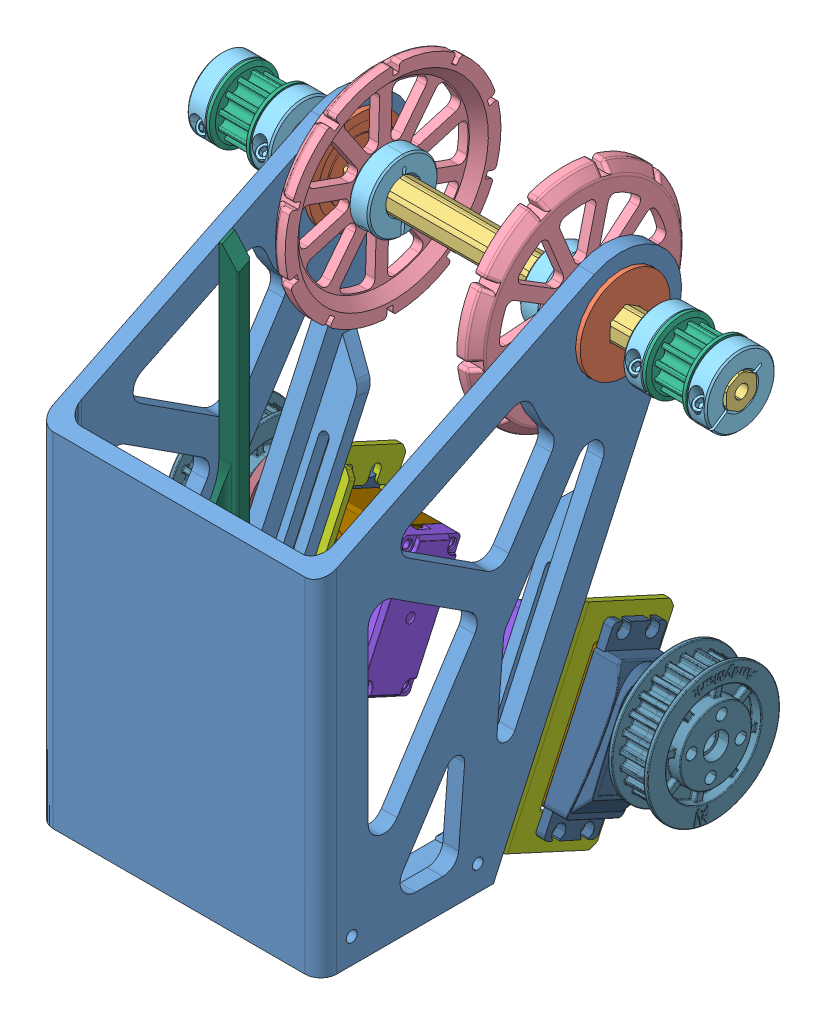
SolidWorks assembly Intake, configuration Default. Lengths in mm.
Overall size (165 189.33 142.34).
35 component instances, 15 part files, 67 mates.
Components (placement in the parent):
- IntakeBody-1: IntakeBody [Default] at (-26.4848 14.4337 189.9954) size (90 153.43 114.54)
- 0_375_Hex_ID_x_1_125_OD_x_0_313_WD_Flanged_Bearing_217-2735.step-1: 0_375_Hex_ID_x_1_125_OD_x_0_313_WD_Flanged_Bearing_217-2735.step [Default] at (-32.8348 143.5737 98.7454) x (0 -0.525688 -0.850678) z (0 -0.850678 0.525688) size (31.12 7.94 31.12)
- 0_375_Hex_ID_x_1_125_OD_x_0_313_WD_Flanged_Bearing_217-2735.step-2: 0_375_Hex_ID_x_1_125_OD_x_0_313_WD_Flanged_Bearing_217-2735.step [Default] at (59.8652 143.5737 98.7454) x (0 0.525688 0.850678) z (0 -0.850678 0.525688) size (31.12 7.94 31.12)
- IntakeHex-1: IntakeHex [Default] at (-360.4391 143.5692 98.7381) x (0 0.999552 -0.02992) z (-1 0 0) size (10.24 9.53 165)
- IntakeWheel-1: IntakeWheel [Default] at (-19.9773 143.4781 98.5907) x (0 0.02992 0.999552) z (1 0 0) size (68.5 68.38 6)
- IntakeWheel-2: IntakeWheel [Default] at (46.6554 143.396 98.7433) x (0 -0.850678 0.525688) z (-1 0 0) size (68.5 68.38 6)
- Clamping_Shaft_Collar_-_3_8_Hex_ID_217-2739.step-1: Clamping_Shaft_Collar_-_3_8_Hex_ID_217-2739.step [Default] at (40.4804 143.7158 98.7337) x (0 -0.999552 0.02992) z (1 0 0) size (22.21 22.23 6.35)
- Clamping_Shaft_Collar_-_3_8_Hex_ID_217-2739.step-2: Clamping_Shaft_Collar_-_3_8_Hex_ID_217-2739.step [Default] at (-13.8023 143.6387 98.6089) x (0 -0.999552 0.02992) z (1 0 0) size (22.21 22.23 6.35)
- intakePulley-1: intakePulley [Default] at (-61.8891 143.6602 98.8854) x (0 -0.850678 0.525688) z (-1 0 0) size (22.2 22.2 13.72)
- intakePulley-2: intakePulley [Default] at (76.4671 143.7423 98.7329) x (0 -0.850678 0.525688) z (-1 0 0) size (22.2 22.2 13.72)
- REV-41-1485 (2).step-1: REV-41-1485 (2).step [Default] at (57.0152 36.4401 108.0667) x (0 -0.908556 0.417762) z (1 0 0) size (62 34 15)
- REV-41-1485 (2).step-2: REV-41-1485 (2).step [Default] at (-29.9848 36.4401 108.0667) x (0 0.908556 -0.417762) z (-1 0 0) size (62 34 15)
- REV-41-1097 (1).STEP-1: REV-41-1097 (1).STEP [Default] at (30.4566 34.9779 104.8867) x (0 -0.417762 -0.908556) z (-1 0 0) size (24.05 54 43.73)
  - A.STEP-1: A.STEP [Default] at origin size (20.15 40.13 8.54)
  - E.STEP-1: E.STEP [Default] at origin size (20.15 40.15 20.1)
  - C.STEP-1: C.STEP [Default] at origin size (24.05 54 13.28)
  - B.STEP-1: B.STEP [Default] at origin size (9 9 4.4)
  - D.STEP-1: D.STEP [Default] at (0 -10.0526 -30.1) x (-1 0 0) z (0 0 1) size (17.21 17.2 14.7)
- REV-41-1097 (1).STEP-2: REV-41-1097 (1).STEP [Default] at (-2.1626 34.9779 104.8867) x (0 0.417762 0.908556) z (1 0 0) size (24.05 54 43.73)
  - A.STEP-1: A.STEP [Default] at origin size (20.15 40.13 8.54)
  - E.STEP-1: E.STEP [Default] at origin size (20.15 40.15 20.1)
  - C.STEP-1: C.STEP [Default] at origin size (24.05 54 13.28)
  - B.STEP-1: B.STEP [Default] at origin size (9 9 4.4)
  - D.STEP-1: D.STEP [Default] at (0 -10.0526 -30.1) x (-1 0 0) z (0 0 1) size (17.21 17.2 14.7)
- IntakeServoHorn-1: IntakeServoHorn [Default] at (-43.8626 44.1112 100.6871) x (0 0.984266 -0.176693) z (0 0.176693 0.984266) size (25 6 25)
- am-3401+24+tooth+HTD+pulley+half+6mm+bore-1: am-3401+24+tooth+HTD+pulley+half+6mm+bore [Default] at (-55.3651 25.5759 79.8226) x (-1 0 0) z (0 -0.994181 -0.107721) size (8.91 42 42)
- am-3401+24+tooth+HTD+pulley+half+6mm+bore-2: am-3401+24+tooth+HTD+pulley+half+6mm+bore [Default] at (-55.3651 62.8072 126.1025) x (1 0 0) z (0 -0.107721 0.994181) size (8.91 42 42)
- am-3401+24+tooth+HTD+pulley+half+6mm+bore-3: am-3401+24+tooth+HTD+pulley+half+6mm+bore [Default] at (83.6591 28.2252 125.7796) x (-1 0 0) z (0 0.2192 0.97568) size (8.91 42 42)
- am-3401+24+tooth+HTD+pulley+half+6mm+bore-4: am-3401+24+tooth+HTD+pulley+half+6mm+bore [Default] at (83.6591 59.9973 75.5947) x (1 0 0) z (0 0.97568 -0.2192) size (8.91 42 42)
- IntakeServoHorn-2: IntakeServoHorn [Default] at (72.1566 44.1112 100.6871) x (0 -0.97568 0.2192) z (0 0.2192 0.97568) size (25 6 25)
- Clamping_Shaft_Collar_-_3_8_Hex_ID_217-2739.step-7: Clamping_Shaft_Collar_-_3_8_Hex_ID_217-2739.step [Default] at (-65.0641 143.5692 98.7381) x (0 -0.822941 0.568127) z (1 0 0) size (22.21 22.23 6.35)
- Clamping_Shaft_Collar_-_3_8_Hex_ID_217-2739.step-8: Clamping_Shaft_Collar_-_3_8_Hex_ID_217-2739.step [Default] at (-44.9981 143.6602 98.8854) x (0 -0.559091 0.829106) z (1 0 0) size (22.21 22.23 6.35)
- Clamping_Shaft_Collar_-_3_8_Hex_ID_217-2739.step-9: Clamping_Shaft_Collar_-_3_8_Hex_ID_217-2739.step [Default] at (73.2921 143.5692 98.7381) x (0 -0.559091 0.829106) z (1 0 0) size (22.21 22.23 6.35)
- Clamping_Shaft_Collar_-_3_8_Hex_ID_217-2739.step-10: Clamping_Shaft_Collar_-_3_8_Hex_ID_217-2739.step [Default] at (93.3581 143.5692 98.7381) x (0 -0.559091 0.829106) z (1 0 0) size (22.21 22.23 6.35)
- Part2-1: Part2 [Default] at (-26.4848 14.4337 189.9954) x (0 0 -1) z (1 0 0) size (49.9 131.79 6)
Mates (geometry in assembly coordinates):
- Concentric1: concentric: cylinder of IntakeBody-1 through (-26.4848 143.5737 98.7454) axis (-1 0 0) radius 14.4375; cylinder of 0_375_Hex_ID_x_1_125_OD_x_0_313_WD_Flanged_Bearing_217-2735.step-1 through (-32.8348 143.5737 98.7454) axis (1 0 0) radius 14.2748
- Coincident1: coincident: plane of IntakeBody-1 through (-26.4848 14.4337 139.1954) normal (1 0 0); plane of 0_375_Hex_ID_x_1_125_OD_x_0_313_WD_Flanged_Bearing_217-2735.step-1 through (-26.4848 135.3953 85.511) normal (-1 0 0)
- Concentric2: concentric: cylinder of IntakeBody-1 through (53.5152 143.5737 98.7454) axis (1 0 0) radius 14.4375; cylinder of 0_375_Hex_ID_x_1_125_OD_x_0_313_WD_Flanged_Bearing_217-2735.step-2 through (59.8652 143.5737 98.7454) axis (-1 0 0) radius 14.2748
- Coincident2: coincident: plane of IntakeBody-1 through (53.5152 14.4337 139.1954) normal (-1 0 0); plane of 0_375_Hex_ID_x_1_125_OD_x_0_313_WD_Flanged_Bearing_217-2735.step-2 through (53.5152 151.7521 111.9799) normal (1 0 0)
- Coincident3: coincident: plane of 0_375_Hex_ID_x_1_125_OD_x_0_313_WD_Flanged_Bearing_217-2735.step-1 through (-6.9368 140.6783 94.06) normal (0 0.880598 0.473865); plane of IntakeHex-1 through (-817.6391 140.6783 94.06) normal (0 -0.880598 -0.473865)
- Coincident4: coincident: plane of 0_375_Hex_ID_x_1_125_OD_x_0_313_WD_Flanged_Bearing_217-2735.step-1 through (-6.9368 146.1837 93.8952) normal (0 0.02992 0.999552); plane of IntakeHex-1 through (-817.6391 146.1751 93.8954) normal (0 -0.02992 -0.999552)
- Parallel2: parallel: plane of 0_375_Hex_ID_x_1_125_OD_x_0_313_WD_Flanged_Bearing_217-2735.step-2 through (33.9671 149.0792 98.5806) normal (0 -0.880598 -0.473865); plane of IntakeHex-1 through (-817.6391 146.4601 103.4162) normal (0 0.880598 0.473865)
- Coincident6: coincident: plane of IntakeHex-1 through (-817.6391 140.9633 103.5807) normal (0 0.02992 0.999552); plane of IntakeWheel-1 through (-16.9773 140.7901 103.5859) normal (0 -0.02992 -0.999552)
- Coincident7: coincident: plane of IntakeHex-1 through (-817.6391 146.4601 103.4162) normal (0 0.880598 0.473865); plane of IntakeWheel-1 through (-16.9773 146.4601 103.4162) normal (0 -0.880598 -0.473865)
- Coincident8: coincident: plane of IntakeHex-1 through (-817.6391 146.4601 103.4162) normal (0 0.880598 0.473865); plane of IntakeWheel-2 through (43.6554 149.066 98.5735) normal (0 -0.880598 -0.473865)
- Coincident9: coincident: plane of IntakeHex-1 through (-817.6391 149.066 98.5735) normal (0 0.850678 -0.525688); plane of IntakeWheel-2 through (43.6554 146.084 93.7481) normal (0 -0.850678 0.525688)
- Coincident10: coincident: plane of IntakeHex-1 through (-817.6391 138.0724 98.9026) normal (0 -0.850678 0.525688); plane of Clamping_Shaft_Collar_-_3_8_Hex_ID_217-2739.step-1 through (43.6554 138.0724 98.9026) normal (0 0.850678 -0.525688)
- Coincident11: coincident: plane of IntakeHex-1 through (-817.6391 140.6783 94.06) normal (0 -0.880598 -0.473865); plane of Clamping_Shaft_Collar_-_3_8_Hex_ID_217-2739.step-1 through (43.6554 140.7478 93.9308) normal (0 0.880598 0.473865)
- Coincident12: coincident: plane of IntakeWheel-2 through (43.6554 143.396 98.7433) normal (-1 0 0); plane of Clamping_Shaft_Collar_-_3_8_Hex_ID_217-2739.step-1 through (43.6554 143.7158 98.7337) normal (1 0 0)
- Coincident13: coincident: plane of IntakeHex-1 through (-817.6391 140.9633 103.5807) normal (0 0.02992 0.999552); plane of Clamping_Shaft_Collar_-_3_8_Hex_ID_217-2739.step-2 through (-10.6273 140.9633 103.5807) normal (0 -0.02992 -0.999552)
- Coincident14: coincident: plane of IntakeHex-1 through (-817.6391 138.0724 98.9026) normal (0 -0.850678 0.525688); plane of Clamping_Shaft_Collar_-_3_8_Hex_ID_217-2739.step-2 through (-10.6273 137.9953 98.7779) normal (0 0.850678 -0.525688)
- Coincident15: coincident: plane of IntakeWheel-1 through (-16.9773 143.4781 98.5907) normal (1 0 0); plane of Clamping_Shaft_Collar_-_3_8_Hex_ID_217-2739.step-2 through (-16.9773 143.6387 98.6089) normal (-1 0 0)
- Coincident16: coincident: plane of IntakeHex-1 through (-817.6391 140.6783 94.06) normal (0 -0.880598 -0.473865); plane of intakePulley-1 through (-48.1731 140.6783 94.06) normal (0 0.880598 0.473865)
- Coincident17: coincident: plane of IntakeHex-1 through (-817.6391 146.1751 93.8954) normal (0 -0.02992 -0.999552); plane of intakePulley-1 through (-48.1731 146.3482 93.8903) normal (0 0.02992 0.999552)
- Coincident18: coincident: plane of IntakeHex-1 through (-817.6391 140.6783 94.06) normal (0 -0.880598 -0.473865); plane of intakePulley-2 through (90.1831 140.7604 93.9074) normal (0 0.880598 0.473865)
- Coincident19: coincident: plane of IntakeHex-1 through (-817.6391 138.0724 98.9026) normal (0 -0.850678 0.525688); plane of intakePulley-2 through (90.1831 138.0724 98.9026) normal (0 0.850678 -0.525688)
- Coincident22: coincident: plane of IntakeBody-1 through (53.5152 -5.7206 146.1635) normal (0 -0.417762 -0.908556); plane of REV-41-1485 (2).step-1 through (57.0152 43.542 123.5121) normal (0 0.417762 0.908556)
- Parallel3: parallel: plane of IntakeBody-1 through (58.5152 14.4337 193.9954) normal (1 0 0); plane of REV-41-1485 (2).step-1 through (57.0152 36.4401 108.0667) normal (1 0 0)
- Parallel4: parallel: plane of IntakeBody-1 through (-31.4848 14.4337 193.9954) normal (-1 0 0); plane of REV-41-1485 (2).step-2 through (-29.9848 36.4401 108.0667) normal (-1 0 0)
- Coincident25: coincident: plane of IntakeBody-1 through (53.5152 -5.7206 146.1635) normal (0 -0.417762 -0.908556); plane of REV-41-1485 (2).step-2 through (-29.9848 43.542 123.5121) normal (0 0.417762 0.908556)
- Concentric6: concentric: cylinder of REV-41-1485 (2).step-1 through (57.0152 59.5535 99.0899) axis (1 0 0) radius 1.7; cylinder of REV-41-1097 (1).STEP-1/C.STEP-1 through (59.8066 59.5535 99.0899) axis (1 0 0) radius 2.25
- Concentric7: concentric: cylinder of REV-41-1485 (2).step-2 through (-29.9848 59.5535 99.0899) axis (-1 0 0) radius 1.7; cylinder of ? through (-31.5126 59.5535 99.0899) axis (-1 0 0) radius 2.25
- Concentric8: concentric: cylinder of REV-41-1485 (2).step-2 through (-29.9848 55.3759 90.0043) axis (-1 0 0) radius 1.7; cylinder of ? through (-31.5126 55.3759 90.0043) axis (-1 0 0) radius 2.25
- Concentric9: concentric: circle of REV-41-1097 (1).STEP-2/D.STEP-1; circle of IntakeServoHorn-1
- Coincident31: coincident: circle of REV-41-1097 (1).STEP-2/D.STEP-1; plane of IntakeServoHorn-1 through (-45.8626 44.1112 100.6871) normal (1 0 0)
- Coincident32: coincident: plane of IntakeServoHorn-1 through (-48.3626 44.1112 100.6871) normal (-1 0 0); plane of am-3401+24+tooth+HTD+pulley+half+6mm+bore-1 through (-48.3626 44.1916 102.9626) normal (1 0 0)
- Concentric14: concentric: cylinder of IntakeServoHorn-1 through (-38.3626 36.2371 102.1007) axis (-1 0 0) radius 1.6; cylinder of am-3401+24+tooth+HTD+pulley+half+6mm+bore-1 through (-57.2701 36.2371 102.1007) axis (1 0 0) radius 1.778
- Concentric15: concentric: cylinder of am-3401+24+tooth+HTD+pulley+half+6mm+bore-1 through (-57.2701 36.2371 102.1007) axis (1 0 0) radius 1.778; cylinder of am-3401+24+tooth+HTD+pulley+half+6mm+bore-2 through (-53.4601 36.2371 102.1007) axis (-1 0 0) radius 1.778
- Concentric16: concentric: cylinder of am-3401+24+tooth+HTD+pulley+half+6mm+bore-1 through (-57.2701 44.1916 102.9626) axis (1 0 0) radius 3.1; cylinder of am-3401+24+tooth+HTD+pulley+half+6mm+bore-2 through (-53.4601 44.1916 102.9626) axis (-1 0 0) radius 3.1
- Coincident33: coincident: plane of am-3401+24+tooth+HTD+pulley+half+6mm+bore-1 through (-55.3651 45.9927 85.1904) normal (-1 0 0); plane of am-3401+24+tooth+HTD+pulley+half+6mm+bore-2 through (-55.3651 61.937 105.0098) normal (1 0 0)
- Concentric17: concentric: cylinder of am-3401+24+tooth+HTD+pulley+half+6mm+bore-4 through (85.5641 51.9177 98.9333) axis (-1 0 0) radius 1.778; cylinder of IntakeServoHorn-2 through (66.6566 51.9167 98.9335) axis (1 0 0) radius 1.6
- Concentric18: concentric: cylinder of am-3401+24+tooth+HTD+pulley+half+6mm+bore-3 through (81.7541 51.9177 98.9333) axis (1 0 0) radius 1.778; cylinder of am-3401+24+tooth+HTD+pulley+half+6mm+bore-4 through (85.5641 51.9177 98.9333) axis (-1 0 0) radius 1.778
- Coincident34: coincident: plane of am-3401+24+tooth+HTD+pulley+half+6mm+bore-3 through (83.6591 26.7101 104.7234) normal (-1 0 0); plane of am-3401+24+tooth+HTD+pulley+half+6mm+bore-4 through (83.6591 40.3165 83.2317) normal (1 0 0)
- Concentric20: concentric: cylinder of am-3401+24+tooth+HTD+pulley+half+6mm+bore-3 through (81.7541 44.1112 100.6871) axis (1 0 0) radius 3.1; cylinder of am-3401+24+tooth+HTD+pulley+half+6mm+bore-4 through (85.5641 44.1112 100.6871) axis (-1 0 0) radius 3.1
- Coincident35: coincident: plane of am-3401+24+tooth+HTD+pulley+half+6mm+bore-4 through (76.6566 44.1112 100.6871) normal (-1 0 0); plane of IntakeServoHorn-2 through (76.6566 44.1112 100.6871) normal (1 0 0)
- Concentric21: concentric: circle of REV-41-1097 (1).STEP-1/D.STEP-1; cylinder of IntakeServoHorn-2 through (76.6566 44.1112 100.6871) axis (-1 0 0) radius 1.75
- Coincident37: coincident: plane of REV-41-1097 (1).STEP-1/D.STEP-1 through (74.1566 44.1112 100.6871) normal (1 0 0); plane of IntakeServoHorn-2 through (74.1566 44.1112 100.6871) normal (-1 0 0)
- Coincident38: coincident: plane of intakePulley-1 through (-60.3651 143.6602 98.8854) normal (1 0 0); plane of am-3401+24+tooth+HTD+pulley+half+6mm+bore-2 through (-60.3651 44.1916 102.9626) normal (1 0 0)
- Coincident40: coincident: plane of intakePulley-2 through (88.6591 143.7423 98.7329) normal (-1 0 0); plane of am-3401+24+tooth+HTD+pulley+half+6mm+bore-3 through (88.6591 44.1112 100.6871) normal (-1 0 0)
- BeltMate1: belt = 41.492 : 19.431 mm: circle of intakePulley-2; circle of am-3401+24+tooth+HTD+pulley+half+6mm+bore-4
- BeltMate2: belt = 19.431 : 41.492 mm: circle of am-3401+24+tooth+HTD+pulley+half+6mm+bore-2; circle of intakePulley-1
- Concentric23: concentric: cylinder of REV-41-1485 (2).step-1 through (57.0152 55.3759 90.0043) axis (1 0 0) radius 1.7; cylinder of REV-41-1097 (1).STEP-1/C.STEP-1 through (59.8066 55.3759 90.0043) axis (1 0 0) radius 2.25
- Concentric25: concentric: circle of IntakeBody-1; cylinder of REV-41-1485 (2).step-1 through (49.5152 21.7367 133.5384) axis (0 0.417762 0.908556) radius 1.7
- Concentric26: concentric: circle of IntakeBody-1; circle of REV-41-1485 (2).step-2
- Concentric27: concentric: cylinder of am-3401+24+tooth+HTD+pulley+half+6mm+bore-3 through (81.7541 44.1112 100.6871) axis (1 0 0) radius 3.1; cylinder of IntakeServoHorn-2 through (74.1566 44.1112 100.6871) axis (1 0 0) radius 12.5
- Concentric28: concentric: cylinder of IntakeHex-1 through (96.7609 143.5692 98.7381) axis (-1 0 0) radius 2.1; cylinder of Clamping_Shaft_Collar_-_3_8_Hex_ID_217-2739.step-7 through (-61.8891 143.5692 98.7381) axis (-1 0 0) radius 11.1125
- Coincident41: coincident: circle of intakePulley-1; plane of Clamping_Shaft_Collar_-_3_8_Hex_ID_217-2739.step-7 through (-61.8891 143.5692 98.7381) normal (1 0 0)
- Concentric29: concentric: cylinder of intakePulley-1 through (-62.5749 143.6602 98.8854) axis (1 0 0) radius 11.0998; cylinder of Clamping_Shaft_Collar_-_3_8_Hex_ID_217-2739.step-8 through (-41.8231 143.6602 98.8854) axis (-1 0 0) radius 11.1125
- Coincident42: coincident: circle of intakePulley-1; plane of Clamping_Shaft_Collar_-_3_8_Hex_ID_217-2739.step-8 through (-48.1731 143.6602 98.8854) normal (-1 0 0)
- Concentric30: concentric: cylinder of IntakeHex-1 through (96.7609 143.5692 98.7381) axis (-1 0 0) radius 2.1; cylinder of Clamping_Shaft_Collar_-_3_8_Hex_ID_217-2739.step-10 through (96.5331 143.5692 98.7381) axis (-1 0 0) radius 11.1125
- Coincident43: coincident: circle of intakePulley-2; plane of Clamping_Shaft_Collar_-_3_8_Hex_ID_217-2739.step-10 through (90.1831 143.5692 98.7381) normal (-1 0 0)
- Concentric31: concentric: cylinder of IntakeHex-1 through (96.7609 143.5692 98.7381) axis (-1 0 0) radius 2.1; cylinder of Clamping_Shaft_Collar_-_3_8_Hex_ID_217-2739.step-9 through (76.4671 143.5692 98.7381) axis (-1 0 0) radius 11.1125
- Coincident44: coincident: circle of intakePulley-2; plane of Clamping_Shaft_Collar_-_3_8_Hex_ID_217-2739.step-9 through (76.4671 143.5692 98.7381) normal (1 0 0)
- Coincident46: coincident: plane of IntakeHex-1 through (-68.2391 143.5692 98.7381) normal (-1 0 0); plane of Clamping_Shaft_Collar_-_3_8_Hex_ID_217-2739.step-7 through (-68.2391 143.5692 98.7381) normal (-1 0 0)
- InPlace1: in place: plane of IntakeBody-1 through (-26.4848 14.4337 139.1954) normal (0 1 0); plane of ? through (0 14.4337 0) normal (0 1 0); moOrthogonalPlaneRef_w of IntakeBody-1 through (-26.4848 14.4337 139.1954) normal (0 1 0); plane of ? through (0 14.4337 0) normal (0 0 -1); plane of IntakeBody-1 through (-26.4848 14.4337 139.1954) normal (0 1 0); plane of ? through (0 14.4337 0) normal (1 0 0); plane of IntakeBody-1 through (-26.4848 14.4337 139.1954) normal (0 1 0); unknown of ?
- Coincident47: coincident: plane of IntakeBody-1; plane of ?
- Coincident48: coincident: moOrthogonalPlaneRef_w of IntakeBody-1 through (-26.4848 14.4337 189.9954) normal (0 0 -1); plane of ? through (-26.4848 14.4337 189.9954) normal (0 0 -1)
- Coincident49: coincident: moOrthogonalPlaneRef_w of IntakeBody-1 through (-26.4848 14.4337 189.9954) normal (-1 0 0); plane of ? through (-26.4848 14.4337 189.9954) normal (1 0 0)
- InPlace2: in place: plane of IntakeBody-1 through (-26.4848 14.4337 139.1954) normal (1 0 0); plane of ? through (-26.4848 0 0) normal (1 0 0); plane of IntakeBody-1 through (-26.4848 14.4337 139.1954) normal (1 0 0); plane of ? through (-26.4848 0 0) normal (0 1 0); plane of IntakeBody-1 through (-26.4848 14.4337 139.1954) normal (1 0 0); plane of ? through (-26.4848 0 0) normal (0 0 -1); plane of IntakeBody-1 through (-26.4848 14.4337 139.1954) normal (1 0 0); unknown of Part2-1
- Coincident50: coincident: plane of IntakeBody-1; plane of Part2-1
- Coincident51: coincident: moOrthogonalPlaneRef_w of IntakeBody-1 through (-26.4848 14.4337 189.9954) normal (0 1 0); plane of Part2-1 through (-26.4848 14.4337 189.9954) normal (0 1 0)
- Coincident52: coincident: moOrthogonalPlaneRef_w of IntakeBody-1 through (-26.4848 14.4337 189.9954) normal (0 0 1); plane of Part2-1 through (-26.4848 14.4337 189.9954) normal (0 0 -1)
